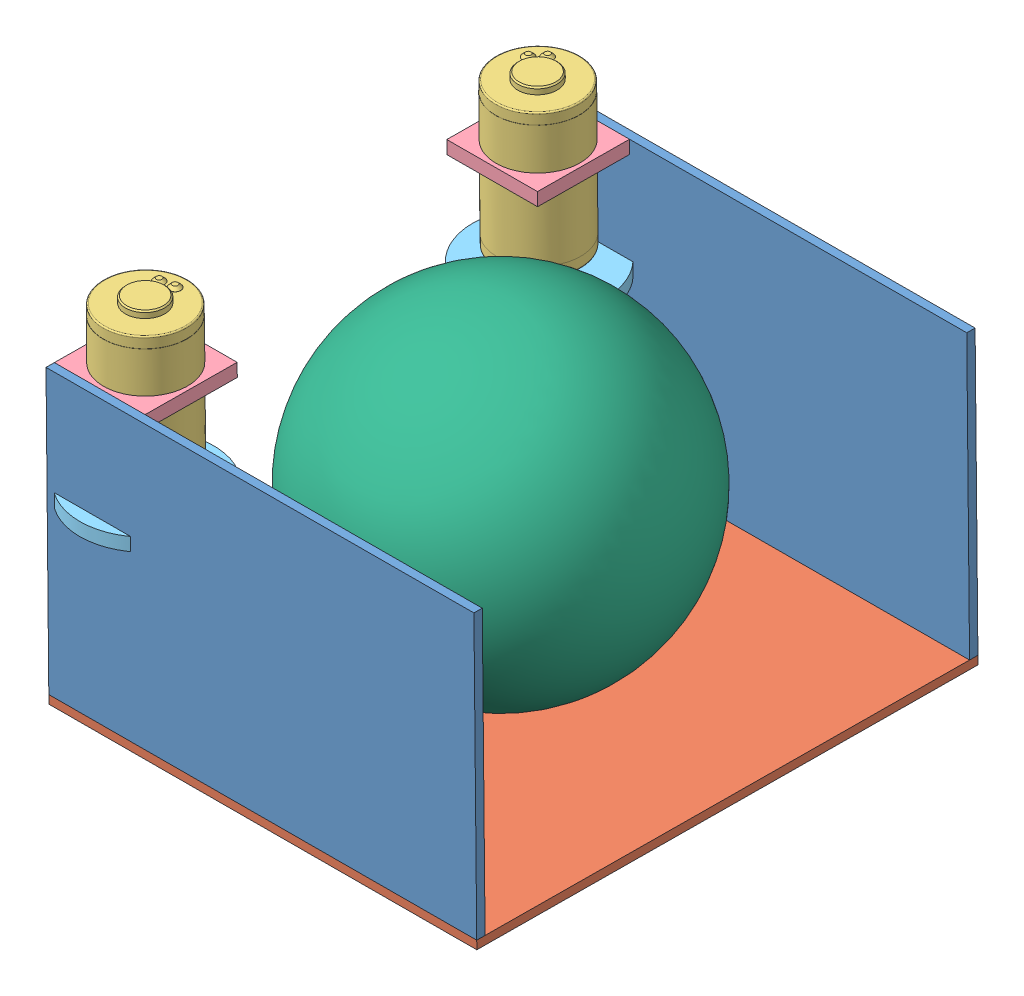
SolidWorks assembly ThrowerBox2-3580300, configuration Default. Lengths in mm.
Overall size (417.04 397.64 434.32).
11 component instances, 6 part files, 1 mates.
Components (placement in the parent):
- ThrowerBoxShort-3580300-1: ThrowerBoxShort-3580300 [Default] at (0.6947 13.6498 -13.2655) x (0.999918 0.010396 0.007444) z (-0.007447 0.000322 0.999972) size (367.04 267.03 431.5)
  - 3580307-1: 3580307 [Default] at (-82.1979 28.1204 24.2701) size (330.2 215.9 6.35)
  - 3580307-2: 3580307 [Default] at (-82.1979 28.1204 -350.3799) x (-1 0 0) z (0 0 -1) size (330.2 215.9 6.35)
  - 3580305-4: 3580305 [Default] at (-82.1979 -83.0046 -163.0549) x (1 0 0) z (0 -1 0) size (330.2 381 6.35)
  - CIM-217-2000-3580300-1: CIM-217-2000-3580300 [Default] at (-212.2979 65.8041 -13.9049) x (0 1 0) z (-0.556008 0 0.831177) size (150.2 64.01 64.01)
  - cim_mount-3580300-1: cim_mount-3580300 [Default] at (-212.2979 126.0704 -13.9049) size (70 10 70)
  - cim_mount-3580300-2: cim_mount-3580300 [Default] at (-212.2979 126.0704 -312.2049) size (70 10 70)
  - 4inwheel-3580300-1: 4inwheel-3580300 [Default] at (-212.2979 46.1084 -312.2049) x (-0.236097 0 -0.971729) z (0.971729 0 -0.236097) size (101.6 10 101.6)
  - 4inwheel-3580300-2: 4inwheel-3580300 [Default] at (-212.2979 46.1084 -13.9049) x (0.713797 0 0.700352) z (-0.700352 0 0.713797) size (101.6 10 101.6)
  - CIM-217-2000-3580300-4: CIM-217-2000-3580300 [Default] at (-212.2979 66.2483 -312.2049) x (0 1 0) z (0 0 1) size (150.2 64.01 64.01)
- ball-3580300-1: ball-3580300 [Default] at (5.8156 -22.0512 -150.0481) x (0.508868 0.735379 0.447517) z (-0.428497 -0.2345 0.872582) size (247.65 247.65 247.65)
Mates (geometry in assembly coordinates):
- Tangent2: tangent anti-aligned: plane of ThrowerBoxShort-3580300-1/3580305-4 through (-79.4524 -67.0826 -176.8958) normal (-0.010394 0.999946 -0.000399); sphere of ball-3580300-1
